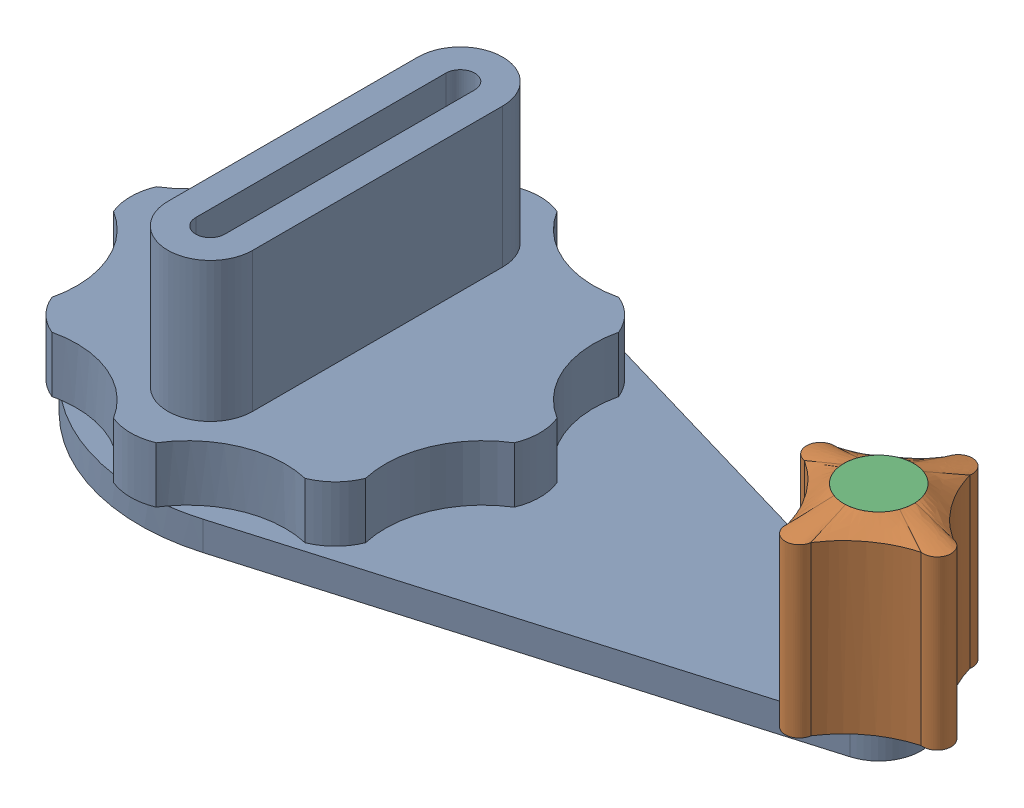
SolidWorks assembly Handle Crank, configuration Default. Lengths in mm.
Overall size (96 31.88 46.58).
3 component instances, 3 part files, 4 mates.
Components (placement in the parent):
- HANDLE-1: HANDLE [Default] at origin size (89.96 31.88 46.58)
- WHEEL AXLE-1: WHEEL AXLE [Default] at (61.849 20.701 0) x (0.151606 0 -0.988441) z (0.988441 0 0.151606) size (19.05 20.65 19.05)
- HANDLE DOWEL-1: HANDLE DOWEL [Default] at (61.849 22.2885 0) x (0.999946 0 0.010354) z (0.010354 0 -0.999946) size (7.94 14.29 7.94)
Mates (geometry in assembly coordinates):
- Concentric12: concentric anti-aligned: circle of 1. HANDLE-1; circle of 2. WHEEL AXLE-1
- Concentric13: concentric anti-aligned: circle of 1. HANDLE-1; circle of 3. HANDLE DOWEL-1
- Coincident12: coincident anti-aligned: plane of 1. HANDLE-1 through (0 1.651 0) normal (0 1 0); plane of 2. WHEEL AXLE-1 through (56.9432 1.651 -11.426) normal (0 -1 0)
- Coincident13: coincident aligned: plane of 1. HANDLE-1 through (61.849 19.1135 0) normal (0 1 0); circle of 3. HANDLE DOWEL-1
